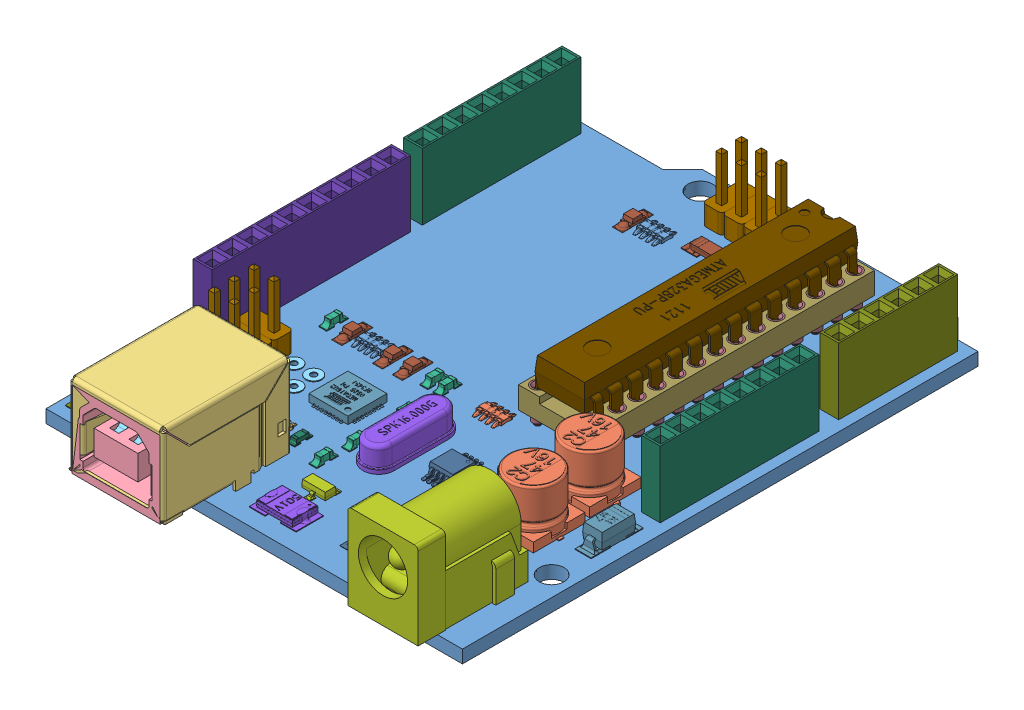
SolidWorks assembly arduino uno, configuration Default. Lengths in mm.
Overall size (53.34 15.65 74.93).
87 component instances, 35 part files, 133 mates.
Components (placement in the parent):
- unoboard blue-1: unoboard blue [Default] at origin size (53.34 1.65 68.58)
- 47uf CAP Dcase-1: 47uf CAP Dcase [Défaut] at (-9.4141 0 -18.4991) x (0 0 -1) z (1 0 0) size (6.6 6.6 7.25)
- USB type b-1: USB type b [Default] at (-38.02 0.83 6.35) size (13.72 15.2 16.5)
  - USB SHELL-1: USB SHELL [Default] at origin size (13.72 15.2 16.5)
  - USB core-1: USB core [Défaut] at origin size (11.3 10.68 15.75)
  - usb top contact-1: usb top contact [Default] at (1.25 5.69 0.01) size (1 9.67 13.76)
  - usb btm contact-1: usb btm contact [Default] at (1.25 4.01 -0.69) size (1 6.84 11.76)
  - usb btm contact-2: usb btm contact [Default] at (-1.25 4.01 -0.69) size (1 6.84 11.76)
  - usb top contact-2: usb top contact [Default] at (-1.25 5.69 0.01) size (1 9.67 13.76)
- power jack-1: power jack [Défaut] at (-7.675 0 2.5) size (9.45 15.2 14.2)
- 47uf CAP Dcase-2: 47uf CAP Dcase [Défaut] at (-9.4141 0.3 -25.7132) x (0 0 -1) z (1 0 0) size (6.6 6.6 7.25)
- crystal-1: crystal [Default] at (-26.162 0 -18.923) x (1 0 0) z (0 0 -1) size (4 5 11)
- 2pin_header__02-1: 2pin_header__02 [Default] at (-46.23 0 -15.75) size (5 11.75 2.54)
- nano - reg-1: nano - reg [Default] at (-17.399 0 -7.747) size (6.5 1.69 8.3)
- led 0805-1: led 0805 [Default] at (-34.29 0 -27.94) x (0 0 1) z (-1 0 0) size (4 0.86 1.35)
- 2pin_header__02-2: 2pin_header__02 [Default] at (-30.43 0 -64.91) x (0 0 1) z (-1 0 0) size (5 11.75 2.54)
- dip28-1: dip28 [Default] at (-16.383 1.5 -46.355) x (0 0 -1) z (1 0 0) size (35.48 7.37 10.1)
  - dip28-1: dip28 [Default] at origin size (35.48 2.8 10.1)
  - dip socket pin-1: dip socket pin [Default] at (16.51 2.8 -3.81) size (1.7 7.37 1.7)
  - dip socket pin-2: dip socket pin [Default] at (16.51 2.8 3.81) size (1.7 7.37 1.7)
  - dip socket pin-3: dip socket pin [Default] at (13.97 2.8 -3.81) size (1.7 7.37 1.7)
  - dip socket pin-4: dip socket pin [Default] at (13.97 2.8 3.81) size (1.7 7.37 1.7)
  - dip socket pin-5: dip socket pin [Default] at (11.43 2.8 -3.81) size (1.7 7.37 1.7)
  - dip socket pin-6: dip socket pin [Default] at (11.43 2.8 3.81) size (1.7 7.37 1.7)
  - dip socket pin-7: dip socket pin [Default] at (8.89 2.8 -3.81) size (1.7 7.37 1.7)
  - dip socket pin-8: dip socket pin [Default] at (8.89 2.8 3.81) size (1.7 7.37 1.7)
  - dip socket pin-9: dip socket pin [Default] at (6.35 2.8 -3.81) size (1.7 7.37 1.7)
  - dip socket pin-10: dip socket pin [Default] at (6.35 2.8 3.81) size (1.7 7.37 1.7)
  - dip socket pin-11: dip socket pin [Default] at (3.81 2.8 -3.81) size (1.7 7.37 1.7)
  - dip socket pin-12: dip socket pin [Default] at (3.81 2.8 3.81) size (1.7 7.37 1.7)
  - dip socket pin-13: dip socket pin [Default] at (1.27 2.8 -3.81) size (1.7 7.37 1.7)
  - dip socket pin-14: dip socket pin [Default] at (1.27 2.8 3.81) size (1.7 7.37 1.7)
  - dip socket pin-15: dip socket pin [Default] at (-1.27 2.8 -3.81) size (1.7 7.37 1.7)
  - dip socket pin-16: dip socket pin [Default] at (-1.27 2.8 3.81) size (1.7 7.37 1.7)
  - dip socket pin-17: dip socket pin [Default] at (-3.81 2.8 -3.81) size (1.7 7.37 1.7)
  - dip socket pin-18: dip socket pin [Default] at (-3.81 2.8 3.81) size (1.7 7.37 1.7)
  - dip socket pin-19: dip socket pin [Default] at (-6.35 2.8 -3.81) size (1.7 7.37 1.7)
  - dip socket pin-20: dip socket pin [Default] at (-6.35 2.8 3.81) size (1.7 7.37 1.7)
  - dip socket pin-21: dip socket pin [Default] at (-8.89 2.8 -3.81) size (1.7 7.37 1.7)
  - dip socket pin-22: dip socket pin [Default] at (-8.89 2.8 3.81) size (1.7 7.37 1.7)
  - dip socket pin-23: dip socket pin [Default] at (-11.43 2.8 -3.81) size (1.7 7.37 1.7)
  - dip socket pin-24: dip socket pin [Default] at (-11.43 2.8 3.81) size (1.7 7.37 1.7)
  - dip socket pin-25: dip socket pin [Default] at (-13.97 2.8 -3.81) size (1.7 7.37 1.7)
  - dip socket pin-26: dip socket pin [Default] at (-13.97 2.8 3.81) size (1.7 7.37 1.7)
  - dip socket pin-27: dip socket pin [Default] at (-16.51 2.8 -3.81) size (1.7 7.37 1.7)
  - dip socket pin-28: dip socket pin [Default] at (-16.51 2.8 3.81) size (1.7 7.37 1.7)
- 2pin_header__02-3: 2pin_header__02 [Default] at (-27.89 0 -64.91) x (0 0 1) z (-1 0 0) size (5 11.75 2.54)
- 2pin_header__02-4: 2pin_header__02 [Default] at (-25.35 0 -64.91) x (0 0 1) z (-1 0 0) size (5 11.75 2.54)
- 2pin_header__02-5: 2pin_header__02 [Default] at (-46.23 0 -18.29) size (5 11.75 2.54)
- 2pin_header__02-6: 2pin_header__02 [Default] at (-46.23 0 -20.83) size (5 11.75 2.54)
- atmega16u2-1: atmega16u2 [Default] at (-34.671 0.06 -20) x (1 0 0) z (0 0 -1) size (5.5 1.01 5.5)
- led 0805-2: led 0805 [Default] at (-36.83 0 -27.94) x (0 0 1) z (-1 0 0) size (4 0.86 1.35)
- led 0805-3: led 0805 [Default] at (-42.037 0 -27.94) x (0 0 1) z (-1 0 0) size (4 0.86 1.35)
- led 0805-4: led 0805 [Default] at (-36.576 0 -58.42) x (0 0 1) z (-1 0 0) size (4 0.86 1.35)
- 8 PORT HEADER-3: 8 PORT HEADER [Default] at (-50.8 0 -45.72) x (0 0 -1) z (1 0 0) size (20.32 10.51 2.41)
- 8 PORT HEADER-4: 8 PORT HEADER [Default] at (-2.54 0 -27.94) x (0 0 -1) z (1 0 0) size (20.32 10.51 2.41)
- 6 PORT HEADER-3: 6 PORT HEADER [Default] at (-2.54 0 -50.8) x (0 0 -1) z (1 0 0) size (15.24 10.51 2.41)
- 10 PORT HEADER-1: 10 PORT HEADER [Default] at (-50.8 0 -18.796) x (0 0 -1) z (1 0 0) size (25.4 10.51 2.41)
- ATMEL328P-1: ATMEL328P [Default] at (-16.383 4.3 -46.355) x (0 0 -1) z (1 0 0) size (35 7.27 7.87)
- 102 RESISTOR PACK-1: 102 RESISTOR PACK [Default] at (-33.782 0 -58.42) size (3.2 0.46 3)
- 102 RESISTOR PACK-2: 102 RESISTOR PACK [Default] at (-39.37 0 -27.94) size (3.2 0.46 3)
- 103 RESISTOR PACK-3: 103 RESISTOR PACK [Default] at (-23.876 0 -27.94) size (3.2 0.46 3)
- 220 RESISTOR PACK-1: 220 RESISTOR PACK [Default] at (-36.83 0 -12.827) size (3.2 0.46 3)
- 16mhz crystal - measured-1: 16mhz crystal - measured [Default] at (-24.892 0 -41.275) x (0 0 -1) z (1 0 0) size (3.4 0.8 2)
- PADS001-1: PADS001 [Default] at (-39.878 0.1 -18.288) x (-1 0 0) z (0 0 1) size (4.54 0.1 4.54)
- 603 cap on pad-1: 603 cap on pad [Défaut] at (-44.45 0 -27.94) x (0 0 -1) z (1 0 0) size (2.76 0.91 1.12)
- ssot3-1: ssot3 [Default] at (-26.5 0 -8.128) x (-1 0 0) z (0 0 -1) size (3 1.13 3.09)
- mf-msmf050-2-1: mf-msmf050-2 [Default] at (-26.5 0 -4.064) size (5.77 1.02 3.72)
- 603 cap on pad-2: 603 cap on pad [Défaut] at (-29.845 0 -27.94) x (0 0 -1) z (1 0 0) size (2.76 0.91 1.12)
- 603 cap on pad-3: 603 cap on pad [Défaut] at (-31.496 0 -27.94) x (0 0 -1) z (1 0 0) size (2.76 0.91 1.12)
- SOT23-5-1: SOT23-5 [Default] at (-15.24 0 -21.971) x (0 0 -1) z (1 0 0) size (3.7 1.4 2.9)
- 603 cap on pad-4: 603 cap on pad [Défaut] at (-15.24 0 -18.415) size (2.76 0.91 1.12)
- 603 cap on pad-5: 603 cap on pad [Défaut] at (-29.845 0 -12.065) x (0 0 1) z (-1 0 0) size (2.76 0.91 1.12)
- 603 cap on pad-6: 603 cap on pad [Défaut] at (-29.591 0 -22.352) x (0 0 1) z (-1 0 0) size (2.76 0.91 1.12)
- 603 cap on pad-7: 603 cap on pad [Défaut] at (-29.591 0 -16.002) x (0 0 1) z (-1 0 0) size (2.76 0.91 1.12)
- 603 cap on pad-8: 603 cap on pad [Défaut] at (-41.91 0 -12.7) x (0 0 1) z (-1 0 0) size (2.76 0.91 1.12)
- lp2985dgkr-1: lp2985dgkr [Default] at (-20.32 0 -19.05) x (0 0 -1) z (1 0 0) size (5.85 1.1 3)
- cd1206 diode-1: cd1206 diode [Default] at (-27.94 0 -59.436) x (0 0 -1) z (1 0 0) size (2.07 0.96 5)
- cd1206 diode-2: cd1206 diode [Default] at (-46.228 0 -13.081) x (0 0 1) z (-1 0 0) size (2.07 0.96 5)
- 603 resistor-1: 603 resistor [Default] at (-29.591 0 -19.05) x (0 0 1) z (-1 0 0) size (2.36 0.61 1.03)
- blm21-1: blm21 [Défaut] at (-45.085 0 -7.62) x (0 0 -1) z (1 0 0) size (2.76 0.96 1.33)
- m7 diode-1: m7 diode [Default] at (-2.794 0 -21.59) x (0 0 -1) z (1 0 0) size (6.66 2.35 2.5)
- MLC0603-1: MLC0603 [Default] at (-33.655 0 -12.827) x (0 0 -1) z (1 0 0) size (2.36 0.6 1.03)
- MLC0603-2: MLC0603 [Default] at (-39.37 0 -12.827) x (0 0 -1) z (1 0 0) size (2.36 0.6 1.03)
- RESET BUTTON-1: RESET BUTTON [Default] at (-49.403 0 -6.35) size (6.2 3.1 9.6)
  - RESET CORE-1: RESET CORE [Default] at (0 0.1 0) x (-1 0 0) z (0 0 -1) size (6.2 3.1 9.6)
  - RESET-1: RESET [Default] at (0 0.1 0) x (0 0 1) z (-1 0 0) size (7.3 2 6.2)
Mates (geometry in assembly coordinates):
- Distance1: distance = 2.5 mm aligned: plane of power jack-1 through (-7.675 0 2.5) normal (0 0 1); plane of unoboard blue-1 through (0 0 0) normal (0 0 1)
- Coincident2: coincident aligned: plane of unoboard blue-1 through (0 0 0) normal (0 1 0); plane of power jack-1 through (-7.675 0 2.5) normal (0 1 0)
- Coincident3: coincident anti-aligned: plane of unoboard blue-1 through (0 0 0) normal (0 1 0); plane of USB type b-1/USB core-1 through (-38.02 0 6.35) normal (0 -1 0)
- Distance2: distance = 6.35 mm aligned: plane of USB type b-1/USB SHELL-1 through (-38.02 0.83 6.35) normal (0 0 1); plane of unoboard blue-1 through (0 0 0) normal (0 0 1)
- Coincident5: coincident aligned: plane of unoboard blue-1 through (0 0 0) normal (0 1 0); plane of 47uf CAP Dcase-1 through (-9.4141 0 -18.4991) normal (0 1 0)
- Parallel1: parallel anti-aligned: plane of unoboard blue-1 through (0 0 0) normal (0 0 1); plane of 47uf CAP Dcase-1 through (-9.4141 0 -18.4991) normal (0 0 -1)
- Coincident7: coincident aligned: plane of 47uf CAP Dcase-2 through (-6.1141 1.5 -22.4132) normal (1 0 0); plane of 47uf CAP Dcase-1 through (-6.1141 1.2 -15.1991) normal (1 0 0)
- Coincident8: coincident anti-aligned: plane of unoboard blue-1 through (0 0 0) normal (0 1 0); plane of 47uf CAP Dcase-2 through (-9.4141 0 -25.7132) normal (0 -1 0)
- Distance3: distance = 3.175 mm aligned: plane of power jack-1 through (-3.175 10.5 -1) normal (1 0 0); plane of unoboard blue-1 through (0 -1.65 0) normal (1 0 0)
- Distance4: distance = 32 mm aligned: plane of USB type b-1/USB SHELL-1 through (-32 0.83 6.35) normal (1 0 0); plane of unoboard blue-1 through (0 -1.65 0) normal (1 0 0)
- Coincident11: coincident anti-aligned: plane of unoboard blue-1 through (0 0 0) normal (0 1 0); plane of crystal-1 through (-26.162 0 -22.423) normal (0 -1 0)
- Concentric1: concentric aligned: cylinder of unoboard blue-1 through (-26.162 -10 -16.383) axis (0 1 0) radius 0.5; cylinder of crystal-1 through (-26.162 -2 -16.383) axis (0 1 0) radius 0.4
- Concentric2: concentric aligned: cylinder of unoboard blue-1 through (-26.162 -10 -21.463) axis (0 1 0) radius 0.5; cylinder of crystal-1 through (-26.162 -2 -21.463) axis (0 1 0) radius 0.4
- Coincident12: coincident anti-aligned: plane of unoboard blue-1 through (0 0 0) normal (0 1 0); plane of 2pin_header__02-1 through (-44.23 0 -14.98) normal (0 -1 0)
- Distance5: distance = 15.75 mm aligned: plane of 2pin_header__02-1 through (-46.23 0 -15.75) normal (0 0 1); plane of assembly through (0 0 0) normal (0 0 1)
- Distance6: distance = 46.23 mm aligned: plane of 2pin_header__02-1 through (-46.23 0 -15.75) normal (1 0 0); plane of assembly through (0 0 0) normal (1 0 0)
- Coincident15: coincident anti-aligned: plane of unoboard blue-1 through (0 0 0) normal (0 1 0); plane of 2pin_header__02-2 through (-31.2 0 -62.91) normal (0 -1 0)
- Distance7: distance = 64.91 mm aligned: plane of 2pin_header__02-2 through (-30.43 0 -64.91) normal (0 0 1); plane of assembly through (0 0 0) normal (0 0 1)
- Distance8: distance = 30.43 mm anti-aligned: plane of 2pin_header__02-2 through (-30.43 0 -64.91) normal (-1 0 0); plane of assembly through (0 0 0) normal (1 0 0)
- Coincident19: coincident anti-aligned: plane of unoboard blue-1 through (0 0 0) normal (0 1 0); plane of nano - reg-1 through (-17.399 0 -7.747) normal (0 -1 0)
- Concentric3: concentric aligned: cylinder of unoboard blue-1 through (-20.193 -10 -62.865) axis (0 1 0) radius 0.4; cylinder of dip28-1/dip socket pin-1 through (-20.193 33.2926 -62.865) axis (0 1 0) radius 0.25
- Concentric4: concentric aligned: cylinder of unoboard blue-1 through (-12.573 -10 -29.845) axis (0 1 0) radius 0.4; cylinder of dip28-1/dip socket pin-28 through (-12.573 33.2926 -29.845) axis (0 1 0) radius 0.25
- Distance9: distance = 1.5 mm anti-aligned: plane of dip28-1/dip28-1 through (-11.333 1.5 -64.095) normal (0 -1 0); plane of unoboard blue-1 through (0 0 0) normal (0 1 0)
- Coincident21: coincident anti-aligned: plane of unoboard blue-1 through (0 0 0) normal (0 1 0); plane of atmega16u2-1 through (-34.671 0 -20) normal (0 -1 0)
- Distance10: distance = 20 mm anti-aligned: plane of atmega16u2-1 through (-34.671 0.06 -20) normal (0 0 -1); plane of unoboard blue-1 through (0 0 0) normal (0 0 1)
- Distance11: distance = 34.671 mm aligned: plane of atmega16u2-1 through (-34.671 0.06 -20) normal (1 0 0); plane of unoboard blue-1 through (0 0 0) normal (1 0 0)
- Coincident25: coincident anti-aligned: plane of unoboard blue-1 through (0 0 0) normal (0 1 0); plane of led 0805-1 through (-34.29 0 -28.94) normal (0 -1 0)
- Distance12: distance = 34.29 mm anti-aligned: plane of led 0805-1 through (-34.29 0 -27.94) normal (-1 0 0); plane of unoboard blue-1 through (0 0 0) normal (1 0 0)
- Distance13: distance = 27.94 mm aligned: plane of led 0805-1 through (-34.29 0 -27.94) normal (0 0 1); plane of unoboard blue-1 through (0 0 0) normal (0 0 1)
- Coincident28: coincident aligned: plane of led 0805-2 through (-36.83 0 -28.94) normal (0 -1 0); plane of led 0805-3 through (-42.037 0 -28.94) normal (0 -1 0)
- Coincident29: coincident aligned: plane of led 0805-1 through (-34.29 0 -27.94) normal (0 0 1); plane of led 0805-2 through (-36.83 0 -27.94) normal (0 0 1)
- Coincident30: coincident aligned: plane of led 0805-1 through (-34.29 0 -27.94) normal (0 0 1); plane of led 0805-3 through (-42.037 0 -27.94) normal (0 0 1)
- Distance14: distance = 2.54 mm aligned: plane of led 0805-2 through (-36.83 0 -27.94) normal (-1 0 0); plane of led 0805-1 through (-34.29 0 -27.94) normal (-1 0 0)
- Coincident32: coincident anti-aligned: plane of unoboard blue-1 through (0 0 0) normal (0 1 0); plane of led 0805-2 through (-36.83 0 -28.94) normal (0 -1 0)
- Distance15: distance = 42.037 mm anti-aligned: plane of led 0805-3 through (-42.037 0 -27.94) normal (-1 0 0); plane of unoboard blue-1 through (0 0 0) normal (1 0 0)
- Coincident34: coincident anti-aligned: plane of unoboard blue-1 through (0 0 0) normal (0 1 0); plane of led 0805-4 through (-36.576 0 -59.42) normal (0 -1 0)
- Distance16: distance = 36.576 mm anti-aligned: plane of led 0805-4 through (-36.576 0 -58.42) normal (-1 0 0); plane of unoboard blue-1 through (0 0 0) normal (1 0 0)
- Distance17: distance = 58.42 mm aligned: plane of led 0805-4 through (-36.576 0 -58.42) normal (0 0 1); plane of unoboard blue-1 through (0 0 0) normal (0 0 1)
- Coincident37: coincident aligned: plane of unoboard blue-1 through (0 0 0) normal (0 1 0); plane of 8 PORT HEADER-4 through (-2.54 0 -27.94) normal (0 1 0)
- Coincident38: coincident aligned: plane of unoboard blue-1 through (0 0 0) normal (0 1 0); plane of 8 PORT HEADER-3 through (-50.8 0 -45.72) normal (0 1 0)
- Parallel2: parallel aligned: plane of unoboard blue-1 through (0 0 0) normal (1 0 0); plane of 8 PORT HEADER-4 through (-2.54 0 -27.94) normal (1 0 0)
- Parallel3: parallel aligned: plane of unoboard blue-1 through (0 0 0) normal (1 0 0); plane of 8 PORT HEADER-3 through (-50.8 0 -45.72) normal (1 0 0)
- Concentric5: concentric aligned: cylinder of unoboard blue-1 through (-2.54 -1.65 -27.94) axis (0 1 0) radius 0.4; line of 8 PORT HEADER-4 through (-2.54 -2.5255 -27.94) axis (0 1 0)
- Concentric6: concentric aligned: cylinder of unoboard blue-1 through (-50.8 -1.65 -45.72) axis (0 1 0) radius 0.4; line of 8 PORT HEADER-3 through (-50.8 -2.5255 -45.72) axis (0 1 0)
- Coincident43: coincident aligned: plane of unoboard blue-1 through (0 0 0) normal (0 1 0); plane of 10 PORT HEADER-1 through (-50.8 0 -18.796) normal (0 1 0)
- Coincident44: coincident aligned: plane of unoboard blue-1 through (0 0 0) normal (0 1 0); plane of 6 PORT HEADER-3 through (-2.54 0 -50.8) normal (0 1 0)
- Parallel4: parallel aligned: plane of unoboard blue-1 through (0 0 0) normal (1 0 0); plane of 6 PORT HEADER-3 through (-2.54 0 -50.8) normal (1 0 0)
- Parallel5: parallel aligned: plane of unoboard blue-1 through (0 0 0) normal (1 0 0); plane of 10 PORT HEADER-1 through (-50.8 0 -18.796) normal (1 0 0)
- Concentric7: concentric aligned: cylinder of unoboard blue-1 through (-50.8 -1.65 -18.796) axis (0 1 0) radius 0.4; line of 10 PORT HEADER-1 through (-50.8 -2.5255 -18.796) axis (0 1 0)
- Concentric9: concentric aligned: cylinder of unoboard blue-1 through (-2.54 -1.65 -50.8) axis (0 1 0) radius 0.4; line of 6 PORT HEADER-3 through (-2.54 -2.5255 -50.8) axis (0 1 0)
- Coincident50: coincident aligned: plane of dip28-1/dip28-1 through (-16.383 1.5 -46.355) normal (0 0 -1); plane of ATMEL328P-1 through (-16.383 4.3 -46.355) normal (0 0 -1)
- Coincident51: coincident aligned: plane of dip28-1 through (-16.383 1.5 -46.355) normal (1 0 0); plane of ATMEL328P-1 through (-16.383 4.3 -46.355) normal (1 0 0)
- Coincident52: coincident aligned: plane of dip28-1/dip28-1 through (-11.333 4.3 -64.095) normal (0 1 0); plane of ATMEL328P-1 through (-16.383 4.3 -46.355) normal (0 1 0)
- Distance18: distance = 7.747 mm: plane of nano - reg-1 through (-17.399 0 -7.747) normal (0 0 1); line of unoboard blue-1 through (0 53.34 -53.34) axis (0 0 1)
- Distance19: distance = 17.399 mm aligned: plane of nano - reg-1 through (-17.399 0 -7.747) normal (1 0 0); plane of unoboard blue-1 through (0 0 0) normal (1 0 0)
- Coincident55: coincident anti-aligned: plane of unoboard blue-1 through (0 0 0) normal (0 1 0); plane of 102 RESISTOR PACK-1 through (-33.982 0 -59.12) normal (0 -1 0)
- Distance20: distance = 33.782 mm aligned: plane of 102 RESISTOR PACK-1 through (-33.782 0 -58.42) normal (1 0 0); plane of unoboard blue-1 through (0 0 0) normal (1 0 0)
- Distance21: distance = 58.42 mm aligned: plane of 102 RESISTOR PACK-1 through (-33.782 0 -58.42) normal (0 0 1); plane of unoboard blue-1 through (0 0 0) normal (0 0 1)
- Coincident58: coincident aligned: plane of 102 RESISTOR PACK-2 through (-39.37 0 -27.94) normal (0 1 0); plane of 103 RESISTOR PACK-3 through (-23.876 0 -27.94) normal (0 1 0)
- Coincident59: coincident aligned: plane of unoboard blue-1 through (0 0 0) normal (0 1 0); plane of 103 RESISTOR PACK-3 through (-23.876 0 -27.94) normal (0 1 0)
- Coincident60: coincident aligned: plane of 102 RESISTOR PACK-2 through (-39.37 0 -27.94) normal (0 0 1); plane of 103 RESISTOR PACK-3 through (-23.876 0 -27.94) normal (0 0 1)
- Distance22: distance = 23.876 mm aligned: plane of 103 RESISTOR PACK-3 through (-23.876 0 -27.94) normal (1 0 0); plane of unoboard blue-1 through (0 0 0) normal (1 0 0)
- Distance23: distance = 39.37 mm aligned: plane of 102 RESISTOR PACK-2 through (-39.37 0 -27.94) normal (1 0 0); plane of unoboard blue-1 through (0 0 0) normal (1 0 0)
- Distance24: distance = 27.94 mm aligned: plane of 102 RESISTOR PACK-2 through (-39.37 0 -27.94) normal (0 0 1); plane of unoboard blue-1 through (0 0 0) normal (0 0 1)
- Distance25: distance = 12.827 mm aligned: plane of 220 RESISTOR PACK-1 through (-36.83 0 -12.827) normal (0 0 1); plane of unoboard blue-1 through (0 0 0) normal (0 0 1)
- Distance26: distance = 36.83 mm aligned: plane of 220 RESISTOR PACK-1 through (-36.83 0 -12.827) normal (1 0 0); plane of unoboard blue-1 through (0 0 0) normal (1 0 0)
- Coincident66: coincident aligned: plane of unoboard blue-1 through (0 0 0) normal (0 1 0); plane of 220 RESISTOR PACK-1 through (-36.83 0 -12.827) normal (0 1 0)
- Coincident67: coincident anti-aligned: plane of unoboard blue-1 through (0 0 0) normal (0 1 0); plane of 16mhz crystal - measured-1 through (-24.892 0 -41.275) normal (0 -1 0)
- Distance27: distance = 41.275 mm anti-aligned: plane of 16mhz crystal - measured-1 through (-24.892 0 -41.275) normal (0 0 -1); plane of unoboard blue-1 through (0 0 0) normal (0 0 1)
- Distance28: distance = 24.892 mm aligned: plane of 16mhz crystal - measured-1 through (-24.892 0 -41.275) normal (1 0 0); plane of unoboard blue-1 through (0 0 0) normal (1 0 0)
- Coincident70: coincident anti-aligned: plane of unoboard blue-1 through (0 0 0) normal (0 1 0); plane of PADS001-1 through (-42.418 0 -18.288) normal (0 -1 0)
- Distance29: distance = 18.288 mm aligned: plane of PADS001-1 through (-39.878 0.1 -18.288) normal (0 0 1); plane of unoboard blue-1 through (0 0 0) normal (0 0 1)
- Distance30: distance = 39.878 mm anti-aligned: plane of PADS001-1 through (-39.878 0.1 -18.288) normal (-1 0 0); plane of unoboard blue-1 through (0 0 0) normal (1 0 0)
- Distance31: distance = 4.064 mm aligned: plane of mf-msmf050-2-1 through (-26.5 0 -4.064) normal (0 0 1); plane of unoboard blue-1 through (0 0 0) normal (0 0 1)
- Distance32: distance = 26.5 mm aligned: plane of mf-msmf050-2-1 through (-26.5 0 -4.064) normal (1 0 0); plane of unoboard blue-1 through (0 0 0) normal (1 0 0)
- Coincident72: coincident aligned: plane of unoboard blue-1 through (0 0 0) normal (0 1 0); plane of mf-msmf050-2-1 through (-26.5 0 -4.064) normal (0 1 0)
- Distance33: distance = 8.128 mm anti-aligned: plane of unoboard blue-1 through (0 0 0) normal (0 0 1); plane of ssot3-1 through (-26.5 0 -8.128) normal (0 0 -1)
- Coincident74: coincident anti-aligned: plane of ssot3-1 through (-26.5 0 -8.128) normal (-1 0 0); plane of mf-msmf050-2-1 through (-26.5 0 -4.064) normal (1 0 0)
- Coincident75: coincident aligned: plane of unoboard blue-1 through (0 0 0) normal (0 1 0); plane of ssot3-1 through (-26.5 0 -8.128) normal (0 1 0)
- Coincident76: coincident anti-aligned: plane of led 0805-1 through (-34.29 0 -27.94) normal (0 0 1); plane of 603 cap on pad-1 through (-44.45 0 -27.94) normal (0 0 -1)
- Coincident77: coincident aligned: plane of unoboard blue-1 through (0 0 0) normal (0 1 0); plane of 603 cap on pad-1 through (-44.45 0 -27.94) normal (0 1 0)
- Distance34: distance = 44.45 mm aligned: plane of 603 cap on pad-1 through (-44.45 0 -27.94) normal (1 0 0); plane of unoboard blue-1 through (0 0 0) normal (1 0 0)
- Coincident79: coincident aligned: plane of 603 cap on pad-2 through (-29.845 0 -27.94) normal (0 1 0); plane of 603 cap on pad-3 through (-31.496 0 -27.94) normal (0 1 0)
- Coincident80: coincident aligned: plane of 603 cap on pad-2 through (-29.845 0 -27.94) normal (0 0 -1); plane of 603 cap on pad-3 through (-31.496 0 -27.94) normal (0 0 -1)
- Coincident81: coincident aligned: plane of unoboard blue-1 through (0 0 0) normal (0 1 0); plane of 603 cap on pad-2 through (-29.845 0 -27.94) normal (0 1 0)
- Coincident82: coincident aligned: plane of 603 cap on pad-1 through (-44.45 0 -27.94) normal (0 0 -1); plane of 603 cap on pad-2 through (-29.845 0 -27.94) normal (0 0 -1)
- Distance36: distance = 29.845 mm aligned: plane of 603 cap on pad-2 through (-29.845 0 -27.94) normal (1 0 0); plane of unoboard blue-1 through (0 0 0) normal (1 0 0)
- Distance37: distance = 31.496 mm aligned: plane of 603 cap on pad-3 through (-31.496 0 -27.94) normal (1 0 0); plane of unoboard blue-1 through (0 0 0) normal (1 0 0)
- Distance38: distance = 15.24 mm aligned: plane of unoboard blue-1 through (0 0 0) normal (1 0 0); plane of SOT23-5-1 through (-15.24 0 -21.971) normal (1 0 0)
- Distance39: distance = 21.971 mm anti-aligned: plane of SOT23-5-1 through (-15.24 0 -21.971) normal (0 0 -1); plane of unoboard blue-1 through (0 0 0) normal (0 0 1)
- Coincident88: coincident aligned: plane of unoboard blue-1 through (0 0 0) normal (0 1 0); plane of SOT23-5-1 through (-15.24 0 -21.971) normal (0 1 0)
- Distance40: distance = 18.415 mm aligned: plane of 603 cap on pad-4 through (-15.24 0 -18.415) normal (0 0 1); plane of unoboard blue-1 through (0 0 0) normal (0 0 1)
- Distance41: distance = 15.24 mm aligned: plane of 603 cap on pad-4 through (-15.24 0 -18.415) normal (1 0 0); plane of unoboard blue-1 through (0 0 0) normal (1 0 0)
- Coincident91: coincident aligned: plane of unoboard blue-1 through (0 0 0) normal (0 1 0); plane of 603 cap on pad-4 through (-15.24 0 -18.415) normal (0 1 0)
- Coincident92: coincident aligned: plane of unoboard blue-1 through (0 0 0) normal (0 1 0); plane of 603 cap on pad-7 through (-29.591 0 -16.002) normal (0 1 0)
- Coincident93: coincident aligned: plane of unoboard blue-1 through (0 0 0) normal (0 1 0); plane of 603 cap on pad-6 through (-29.591 0 -22.352) normal (0 1 0)
- Coincident94: coincident aligned: plane of 603 cap on pad-5 through (-29.845 0 -12.065) normal (0 1 0); plane of unoboard blue-1 through (0 0 0) normal (0 1 0)
- Coincident95: coincident aligned: plane of 603 cap on pad-8 through (-41.91 0 -12.7) normal (0 1 0); plane of unoboard blue-1 through (0 0 0) normal (0 1 0)
- Coincident96: coincident aligned: plane of 603 cap on pad-7 through (-29.591 0 -16.002) normal (-1 0 0); plane of 603 cap on pad-6 through (-29.591 0 -22.352) normal (-1 0 0)
- Distance42: distance = 29.591 mm anti-aligned: plane of 603 cap on pad-7 through (-29.591 0 -16.002) normal (-1 0 0); plane of unoboard blue-1 through (0 0 0) normal (1 0 0)
- Distance43: distance = 22.352 mm: plane of 603 cap on pad-6 through (-29.591 0 -22.352) normal (0 0 1); line of unoboard blue-1 through (0 53.34 -53.34) axis (0 0 1)
- Distance44: distance = 16.002 mm aligned: plane of 603 cap on pad-7 through (-29.591 0 -16.002) normal (0 0 1); plane of unoboard blue-1 through (0 0 0) normal (0 0 1)
- Distance45: distance = 29.845 mm anti-aligned: plane of 603 cap on pad-5 through (-29.845 0 -12.065) normal (-1 0 0); plane of unoboard blue-1 through (0 0 0) normal (1 0 0)
- Distance46: distance = 12.065 mm aligned: plane of 603 cap on pad-5 through (-29.845 0 -12.065) normal (0 0 1); plane of unoboard blue-1 through (0 0 0) normal (0 0 1)
- Distance47: distance = 41.91 mm anti-aligned: plane of 603 cap on pad-8 through (-41.91 0 -12.7) normal (-1 0 0); plane of unoboard blue-1 through (0 0 0) normal (1 0 0)
- Distance48: distance = 12.7 mm aligned: plane of 603 cap on pad-8 through (-41.91 0 -12.7) normal (0 0 1); plane of unoboard blue-1 through (0 0 0) normal (0 0 1)
- Distance49: distance = 20.32 mm aligned: plane of lp2985dgkr-1 through (-20.32 0 -19.05) normal (1 0 0); plane of unoboard blue-1 through (0 0 0) normal (1 0 0)
- Distance50: distance = 19.05 mm anti-aligned: plane of lp2985dgkr-1 through (-20.32 0 -19.05) normal (0 0 -1); plane of unoboard blue-1 through (0 0 0) normal (0 0 1)
- Coincident99: coincident aligned: plane of unoboard blue-1 through (0 0 0) normal (0 1 0); plane of lp2985dgkr-1 through (-20.32 0 -19.05) normal (0 1 0)
- Distance51: distance = 27.94 mm aligned: plane of cd1206 diode-1 through (-27.94 0 -59.436) normal (1 0 0); plane of unoboard blue-1 through (0 0 0) normal (1 0 0)
- Distance52: distance = 59.436 mm anti-aligned: plane of cd1206 diode-1 through (-27.94 0 -59.436) normal (0 0 -1); plane of unoboard blue-1 through (0 0 0) normal (0 0 1)
- Coincident102: coincident aligned: plane of unoboard blue-1 through (0 0 0) normal (0 1 0); plane of cd1206 diode-1 through (-27.94 0 -59.436) normal (0 1 0)
- Distance53: distance = 46.228 mm anti-aligned: plane of cd1206 diode-2 through (-46.228 0 -13.081) normal (-1 0 0); plane of unoboard blue-1 through (0 0 0) normal (1 0 0)
- Distance54: distance = 13.081 mm aligned: plane of unoboard blue-1 through (0 0 0) normal (0 0 1); plane of cd1206 diode-2 through (-46.228 0 -13.081) normal (0 0 1)
- Coincident105: coincident aligned: plane of unoboard blue-1 through (0 0 0) normal (0 1 0); plane of cd1206 diode-2 through (-46.228 0 -13.081) normal (0 1 0)
- Distance55: distance = 29.591 mm anti-aligned: plane of 603 resistor-1 through (-29.591 0 -19.05) normal (-1 0 0); plane of unoboard blue-1 through (0 0 0) normal (1 0 0)
- Distance56: distance = 19.05 mm aligned: plane of 603 resistor-1 through (-29.591 0 -19.05) normal (0 0 1); plane of unoboard blue-1 through (0 0 0) normal (0 0 1)
- Coincident108: coincident aligned: plane of unoboard blue-1 through (0 0 0) normal (0 1 0); plane of 603 resistor-1 through (-29.591 0 -19.05) normal (0 1 0)
- Distance57: distance = 7.62 mm anti-aligned: plane of blm21-1 through (-45.085 0 -7.62) normal (0 0 -1); plane of unoboard blue-1 through (0 0 0) normal (0 0 1)
- Distance58: distance = 45.085 mm aligned: plane of blm21-1 through (-45.085 0 -7.62) normal (1 0 0); plane of unoboard blue-1 through (0 0 0) normal (1 0 0)
- Distance59: distance = 21.59 mm anti-aligned: plane of m7 diode-1 through (-2.794 0 -21.59) normal (0 0 -1); plane of unoboard blue-1 through (0 0 0) normal (0 0 1)
- Distance60: distance = 2.794 mm aligned: plane of m7 diode-1 through (-2.794 0 -21.59) normal (1 0 0); plane of unoboard blue-1 through (0 0 0) normal (1 0 0)
- Coincident113: coincident aligned: plane of unoboard blue-1 through (0 0 0) normal (0 1 0); plane of m7 diode-1 through (-2.794 0 -21.59) normal (0 1 0)
- Coincident114: coincident anti-aligned: plane of 220 RESISTOR PACK-1 through (-36.83 0 -12.827) normal (0 0 1); plane of MLC0603-1 through (-33.655 0 -12.827) normal (0 0 -1)
- Distance61: distance = 33.655 mm aligned: plane of MLC0603-1 through (-33.655 0 -12.827) normal (1 0 0); plane of unoboard blue-1 through (0 0 0) normal (1 0 0)
- Coincident115: coincident aligned: plane of unoboard blue-1 through (0 0 0) normal (0 1 0); plane of MLC0603-1 through (-33.655 0 -12.827) normal (0 1 0)
- Coincident116: coincident aligned: plane of unoboard blue-1 through (0 0 0) normal (0 1 0); plane of blm21-1 through (-45.085 0 -7.62) normal (0 1 0)
- Coincident117: coincident anti-aligned: plane of 220 RESISTOR PACK-1 through (-36.83 0 -12.827) normal (0 0 1); plane of MLC0603-2 through (-39.37 0 -12.827) normal (0 0 -1)
- Coincident118: coincident aligned: plane of unoboard blue-1 through (0 0 0) normal (0 1 0); plane of MLC0603-2 through (-39.37 0 -12.827) normal (0 1 0)
- Distance62: distance = 39.37 mm aligned: plane of MLC0603-2 through (-39.37 0 -12.827) normal (1 0 0); plane of unoboard blue-1 through (0 0 0) normal (1 0 0)
- Distance63: distance = 49.403 mm aligned: plane of RESET BUTTON-1 through (-49.403 0 -6.35) normal (1 0 0); plane of unoboard blue-1 through (0 0 0) normal (1 0 0)
- Distance64: distance = 6.35 mm aligned: plane of RESET BUTTON-1; plane of unoboard blue-1 through (0 0 0) normal (0 0 1)
- Coincident122: coincident aligned: plane of unoboard blue-1 through (0 0 0) normal (0 1 0); plane of RESET BUTTON-1 through (-49.403 0 -6.35) normal (0 1 0)
